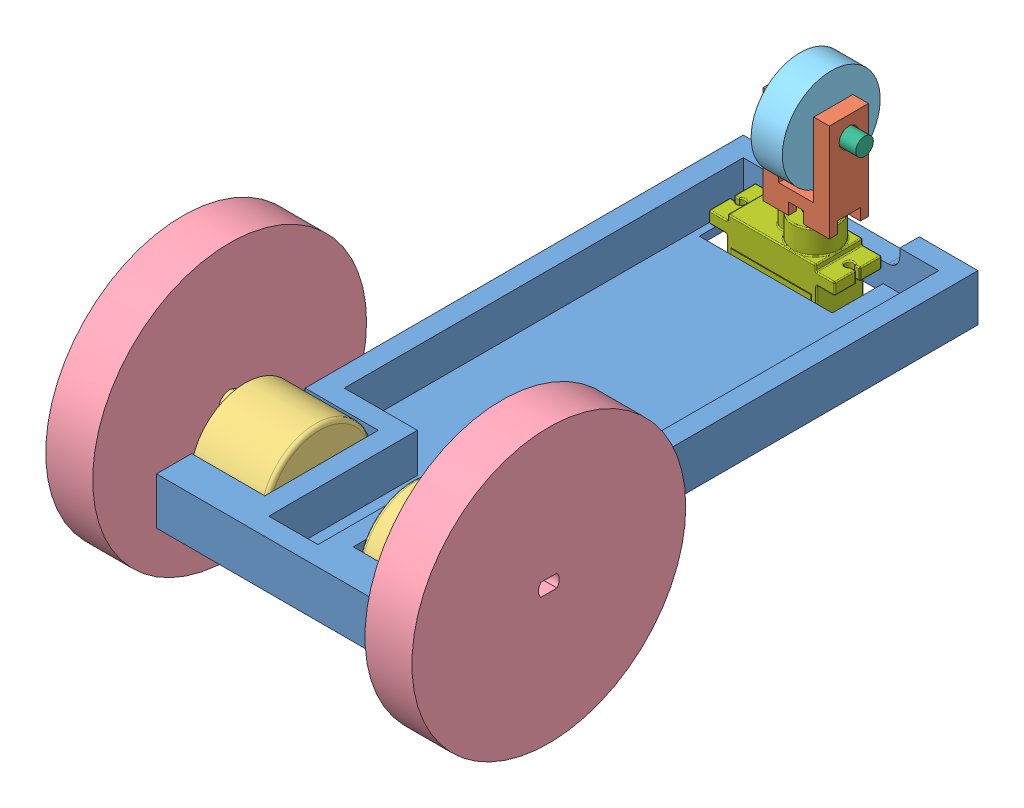
SolidWorks assembly Chassis assembly, configuration Default. Lengths in mm.
Overall size (93.6 70 162.5).
9 component instances, 7 part files, 25 mates.
Components (placement in the parent):
- chassis-1: chassis [Default] at (150 -8.0412 -86.8763) size (67.4 12 150)
- wheel holder-1: wheel holder [Default] at (180 21.9588 -80.3763) x (-1 0 0) z (0 0 1) size (17 25 10)
- 28BYJ48-1: 28BYJ48 [默认] at (149.2 -4.0412 39.6237) x (0 0 -1) z (1 0 0) size (42 32 29)
- 28BYJ48-2: 28BYJ48 [默认] at (210.8 -4.0412 39.6237) x (0 0 1) z (-1 0 0) size (42 32 29)
- stepper wheel-1: stepper wheel [Default] at (145.2 3.9588 39.6237) size (12 70 70)
- stepper wheel-2: stepper wheel [Default] at (226.8 3.9588 39.6237) size (12 70 70)
- servo wheel-1: servo wheel [Default] at (176 26.4588 -75.3763) size (8 25 25)
- servo shaft-1: servo shaft [Default] at (171.5 26.4588 -75.3763) x (1 0 0) z (0 -0.284834 0.958577) size (21 4.5 4.5)
- Servo-MG90S-1: Servo-MG90S [Default] at (174.75 -23.0412 -75.3763) size (32.2 32.5 12.4)
Mates (geometry in assembly coordinates):
- Parallel1: parallel aligned: plane of chassis-1 through (150 -10.0412 -86.8763) normal (0 -1 0); plane of wheel holder-1 through (180 9.4588 -70.3763) normal (0 -1 0)
- Parallel2: parallel aligned: plane of chassis-1 through (150 1.9588 -86.8763) normal (-1 0 0); plane of wheel holder-1 through (171.5 21.9588 -70.3763) normal (-1 0 0)
- Parallel3: parallel aligned: plane of chassis-1 through (150 1.9588 -86.8763) normal (-1 0 0); plane of 28BYJ48-1 through (149.2 -4.0412 39.6237) normal (-1 0 0)
- Parallel4: parallel aligned: plane of chassis-1 through (150 -10.0412 -86.8763) normal (0 -1 0); plane of 28BYJ48-1 through (164.2 -22.0412 32.3237) normal (0 -1 0)
- Coincident4: coincident anti-aligned: plane of chassis-1 through (150 1.9588 -86.8763) normal (-1 0 0); plane of 28BYJ48-1 through (150 -4.0412 57.1237) normal (1 0 0)
- Concentric1: concentric anti-aligned: cylinder of chassis-1 through (146.3 -4.0412 57.1237) axis (1 0 0) radius 2; cylinder of 28BYJ48-1 through (150 -4.0412 57.1237) axis (-1 0 0) radius 2
- Coincident5: coincident anti-aligned: plane of chassis-1 through (210 1.9588 -86.8763) normal (1 0 0); plane of 28BYJ48-2 through (210 -4.0412 22.1237) normal (-1 0 0)
- Parallel5: parallel aligned: plane of chassis-1 through (150 -10.0412 -86.8763) normal (0 -1 0); plane of 28BYJ48-2 through (195.8 -22.0412 46.9237) normal (0 -1 0)
- Concentric2: concentric anti-aligned: cylinder of chassis-1 through (213.7 -4.0412 22.1237) axis (-1 0 0) radius 2; cylinder of 28BYJ48-2 through (210 -4.0412 22.1237) axis (1 0 0) radius 2
- Parallel6: parallel aligned: plane of 28BYJ48-2 through (214.8 2.4588 45.7919) normal (0 -1 0); plane of stepper wheel-2 through (214.8 5.6088 39.6237) normal (0 -1 0)
- Concentric3: concentric anti-aligned: cylinder of 28BYJ48-2 through (220.8 3.9588 39.6237) axis (-1 0 0) radius 2.5; cylinder of stepper wheel-2 through (214.8 3.9588 39.6237) axis (1 0 0) radius 35
- Coincident7: coincident anti-aligned: plane of 28BYJ48-2 through (214.8 -4.0412 39.6237) normal (1 0 0); plane of stepper wheel-2 through (214.8 3.9588 39.6237) normal (-1 0 0)
- Parallel7: parallel aligned: plane of 28BYJ48-1 through (145.2 2.4588 33.4555) normal (0 -1 0); plane of stepper wheel-1 through (133.2 5.6088 39.6237) normal (0 -1 0)
- Concentric4: concentric aligned: cylinder of 28BYJ48-1 through (139.2 3.9588 39.6237) axis (1 0 0) radius 2.5; cylinder of stepper wheel-1 through (133.2 3.9588 39.6237) axis (1 0 0) radius 35
- Coincident8: coincident anti-aligned: plane of 28BYJ48-1 through (145.2 -4.0412 39.6237) normal (-1 0 0); plane of stepper wheel-1 through (145.2 3.9588 39.6237) normal (1 0 0)
- Concentric5: concentric anti-aligned: cylinder of wheel holder-1 through (171.5 26.4588 -75.3763) axis (1 0 0) radius 2.5; cylinder of servo wheel-1 through (184 26.4588 -75.3763) axis (-1 0 0) radius 2.5
- Width1: width anti-aligned: plane of servo wheel-1 through (176 26.4588 -75.3763) normal (-1 0 0); plane of wheel holder-1 through (184 26.4588 -75.3763) normal (1 0 0); plane of servo wheel-1 through (175.5 21.9588 -70.3763) normal (1 0 0); plane of wheel holder-1 through (184.5 21.9588 -70.3763) normal (-1 0 0)
- Width2: width anti-aligned: plane of chassis-1 through (210 1.9588 -86.8763) normal (1 0 0); plane of wheel holder-1 through (150 1.9588 -86.8763) normal (-1 0 0); plane of chassis-1 through (171.5 21.9588 -70.3763) normal (-1 0 0); plane of wheel holder-1 through (188.5 21.9588 -70.3763) normal (1 0 0)
- Tangent1: tangent aligned: cylinder of servo wheel-1 through (184 26.4588 -75.3763) axis (-1 0 0) radius 12.5
- Concentric6: concentric anti-aligned: cylinder of wheel holder-1 through (171.5 26.4588 -75.3763) axis (1 0 0) radius 2.5; cylinder of servo shaft-1 through (192.5 26.4588 -75.3763) axis (-1 0 0) radius 2.25
- Coincident9: coincident aligned: plane of wheel holder-1 through (171.5 21.9588 -70.3763) normal (-1 0 0); plane of servo shaft-1 through (171.5 26.4588 -75.3763) normal (-1 0 0)
- Parallel9: parallel aligned: plane of chassis-1 through (150 -10.0412 -86.8763) normal (0 -1 0); plane of Servo-MG90S-1 through (174.75 -23.0412 -75.3763) normal (0 -1 0)
- Concentric7: concentric aligned: line of wheel holder-1 through (180 9.4588 -75.3763) axis (0 -1 0); cylinder of Servo-MG90S-1 through (180 5.9588 -75.3763) axis (0 -1 0) radius 5.75
- Symmetric1: symmetric aligned: plane of chassis-1 through (156.75 1.9588 -68.8763) normal (0 0 -1); plane of Servo-MG90S-1 through (150 1.9588 -81.8763) normal (0 0 1); plane of chassis-1 through (174.75 -23.0412 -75.3763) normal (0 0 1)
- Coincident12: coincident anti-aligned: plane of wheel holder-1 through (180 9.4588 -70.3763) normal (0 -1 0); plane of Servo-MG90S-1 through (180 9.4588 -75.3763) normal (0 1 0)
